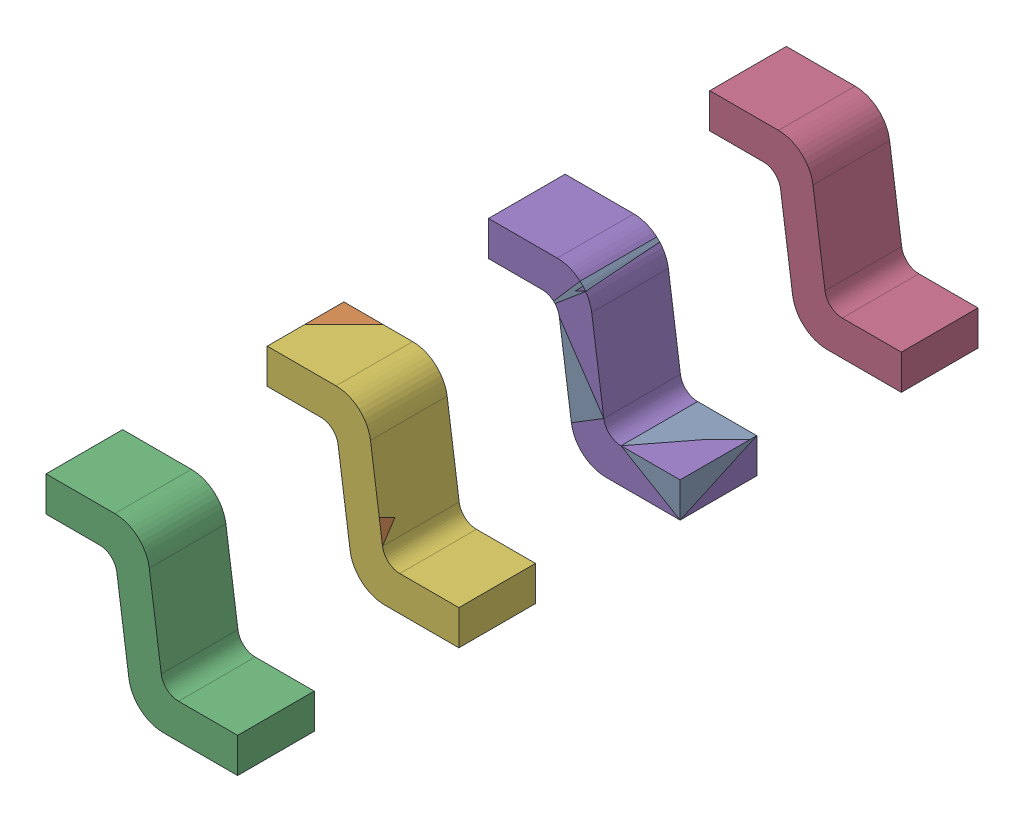
SolidWorks assembly User_Library-HSOP8_Assy_fuss_hsop8_____________, configuration По умолчанию. Lengths in mm.
Overall size (1.1 0.95 4.25).
6 component instances, 1 part files, 0 mates.
Components (placement in the parent):
- User_Library-HSOP8_Fuss_hsop8_____________-1: User_Library-HSOP8_Fuss_hsop8_____________ [По умолчанию] at (0 0 -0.635) size (1.1 0.95 0.44)
- User_Library-HSOP8_Fuss_hsop8_____________-2: User_Library-HSOP8_Fuss_hsop8_____________ [По умолчанию] at (0 0 0.635) size (1.1 0.95 0.44)
- User_Library-HSOP8_Fuss_hsop8_____________-3: User_Library-HSOP8_Fuss_hsop8_____________ [По умолчанию] at (0 0 1.905) size (1.1 0.95 0.44)
- User_Library-HSOP8_Fuss_hsop8_____________-4: User_Library-HSOP8_Fuss_hsop8_____________ [По умолчанию] at (0 0 -1.905) size (1.1 0.95 0.44)
- User_Library-HSOP8_Fuss_hsop8_____________-5: User_Library-HSOP8_Fuss_hsop8_____________ [По умолчанию] at (0 0 -0.635) size (1.1 0.95 0.44)
- User_Library-HSOP8_Fuss_hsop8_____________-6: User_Library-HSOP8_Fuss_hsop8_____________ [По умолчанию] at (0 0 0.635) size (1.1 0.95 0.44)
